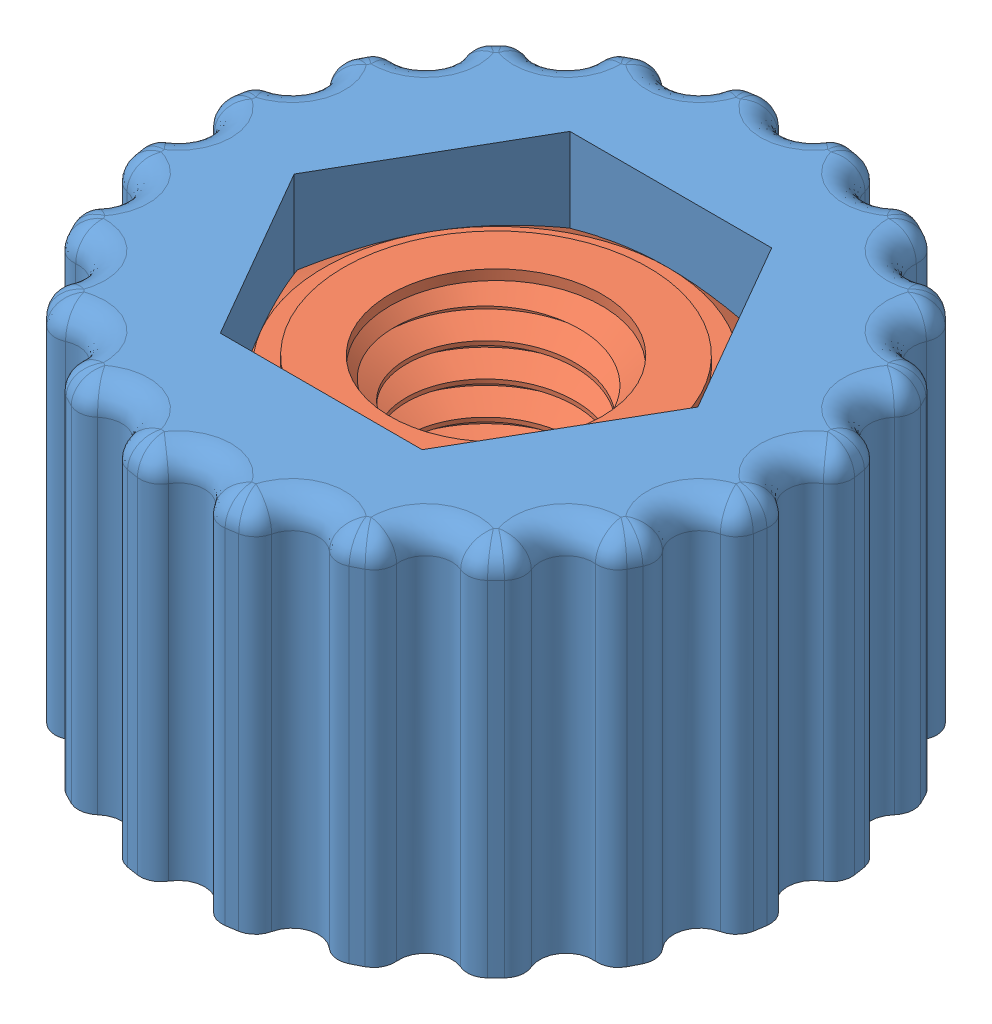
SolidWorks assembly M8_Knob_Short_Assembly_P, configuration Default. Lengths in mm.
Overall size (23.87 14.07 23.87).
2 component instances, 2 part files, 3 mates.
Components (placement in the parent):
- M8_Knob_Short_P-1: M8_Knob_Short_P [Default] at (5.7626 4.8031 20.4066) size (23.87 14.07 23.87)
- M8 x 1.25 Hex Nut-1: M8 x 1.25 Hex Nut [90592A022] at (5.7626 13.0531 20.4066) x (0 0 1) z (-1 0 0) size (13 7.48 15.01)
Mates (geometry in assembly coordinates):
- Concentric1: concentric: circle of M8_Knob_Short_P-1; circle of M8 x 1.25 Hex Nut-1
- Parallel1: parallel: plane of M8_Knob_Short_P-1 through (1.9521 9.8031 13.8066) normal (0.866025 0 0.5); plane of M8 x 1.25 Hex Nut-1 through (2.0098 16.3031 13.9066) normal (-0.866025 0 -0.5)
- Coincident2: coincident anti-aligned: plane of M8_Knob_Short_P-1 through (5.7626 9.8031 20.4066) normal (0 1 0); plane of M8 x 1.25 Hex Nut-1 through (9.5154 9.8031 13.9066) normal (0 -1 0)
